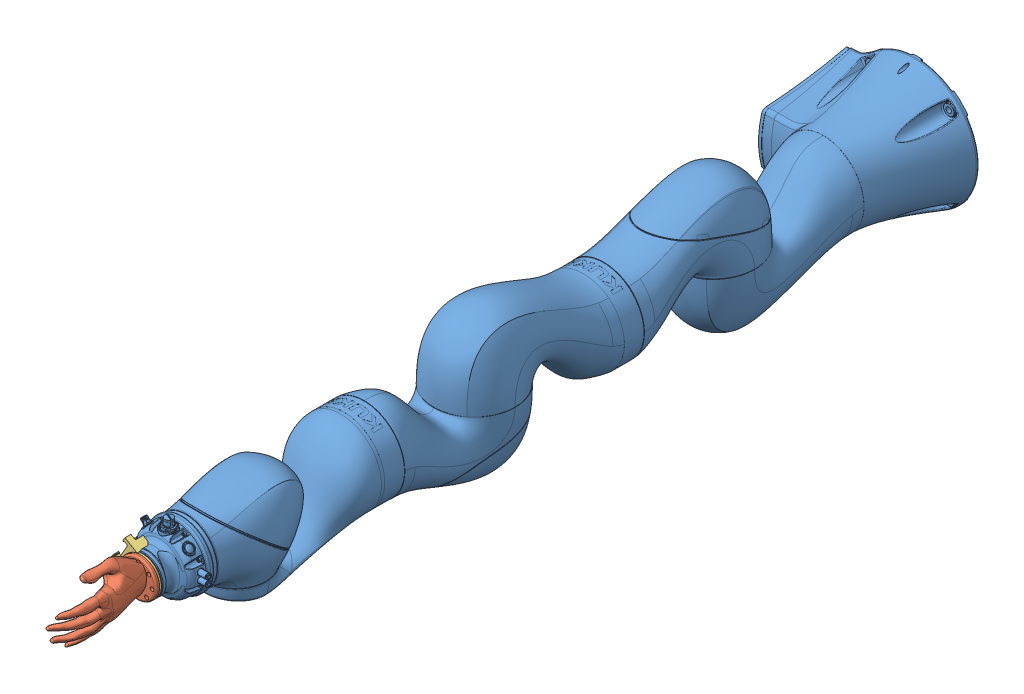
SolidWorks assembly iiwa_finger_fixed, configuration 默认. Lengths in mm.
Overall size (216.96 235.48 1450.23).
3 component instances, 3 part files, 3 mates.
Components (placement in the parent):
- iiwa7 R800 - MF Touch pneumatisch-1: iiwa7 R800 - MF Touch pneumatisch [默认] at (-32.6096 25.2713 646.7291) size (216.96 235.48 1292.53)
- hand-1: hand [默认] at (-173.8199 39.7963 1509.0659) x (0 0 -1) z (0.994086 -0.1086 0) size (154.88 98.38 63)
- frame_IMU-1: frame_IMU [默认] at (-32.6096 25.2713 1943.6159) x (0.862043 -0.506835 0) z (0.506835 0.862043 0) size (76 23.57 63)
Mates (geometry in assembly coordinates):
- 同心1: concentric aligned: cylinder of iiwa7 R800 - MF Touch pneumatisch-1 through (-32.6096 25.2713 1873.8291) axis (0 0 -1) radius 31.5; cylinder of hand-1 through (-32.6096 25.2713 1949.6159) axis (0 0 -1) radius 31.5
- 同心2: concentric anti-aligned: cylinder of iiwa7 R800 - MF Touch pneumatisch-1 through (-32.6096 25.2713 1873.8291) axis (0 0 -1) radius 31.5; cylinder of frame_IMU-1 through (-32.6096 25.2713 1940.6159) axis (0 0 1) radius 31.5
- 重合3: coincident anti-aligned: plane of hand-1 through (-32.9881 26.6298 1943.6159) normal (0 0 -1); plane of frame_IMU-1 through (-32.6096 25.2713 1943.6159) normal (0 0 1)
